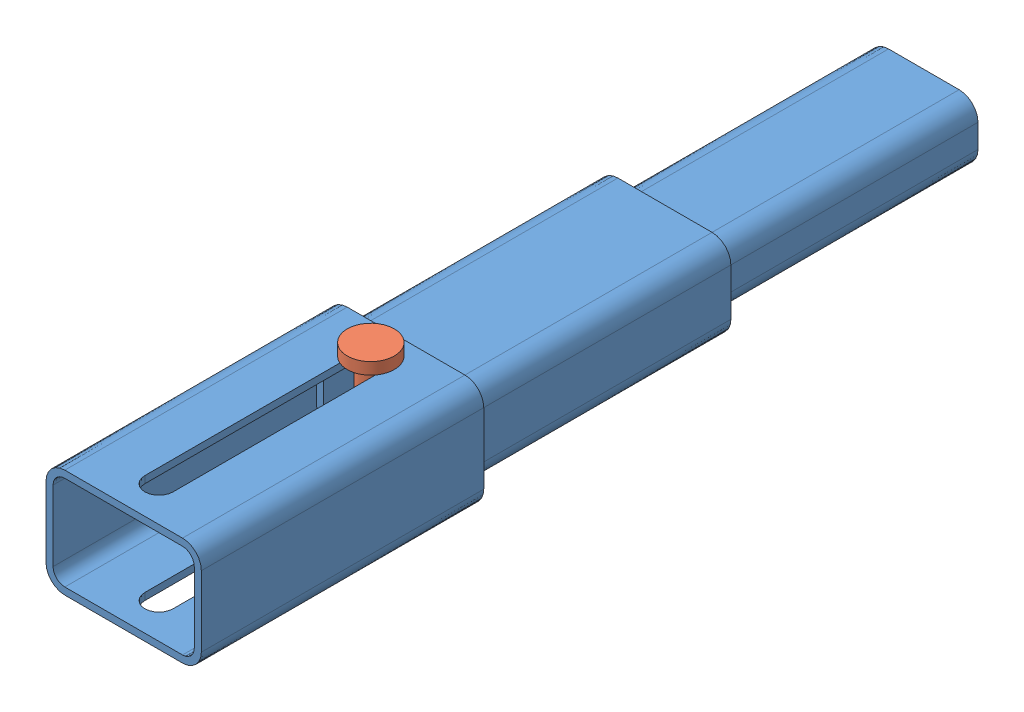
SolidWorks assembly advanced and mechanical mates, configuration Default. Lengths in mm.
Overall size (66 60 340).
4 component instances, 2 part files, 9 mates.
Components (placement in the parent):
- Advanced mates-1: Advanced mates [Large] at (58.4003 66.2101 82.4925) size (66 46 120)
- pin-1: pin [Default] at (58.4003 41.2101 37.4925) x (0.932523 0 -0.361112) z (0.361112 0 0.932523) size (20 60 20)
- Advanced mates-3: Advanced mates [Medium] at (58.4003 66.2101 -27.5075) size (56 36 120)
- Advanced mates-4: Advanced mates [Small] at (58.4003 66.2101 -137.5075) size (46 26 120)
Mates (geometry in assembly coordinates):
- Width1: width aligned: plane of Advanced mates-1 through (83.4003 46.2101 142.4925) normal (0 1 0); plane of Advanced mates-1 through (83.4003 86.2101 142.4925) normal (0 -1 0); plane of Advanced mates-3 through (78.4003 84.2101 32.4925) normal (0 1 0); plane of Advanced mates-3 through (78.4003 48.2101 32.4925) normal (0 -1 0)
- Width2: width anti-aligned: plane of Advanced mates-1 through (28.4003 51.2101 142.4925) normal (1 0 0); plane of Advanced mates-1 through (88.4003 51.2101 142.4925) normal (-1 0 0); plane of Advanced mates-3 through (30.4003 56.2101 32.4925) normal (-1 0 0); plane of Advanced mates-3 through (86.4003 56.2101 32.4925) normal (1 0 0)
- Width3: width anti-aligned: plane of Advanced mates-3 through (78.4003 81.2101 32.4925) normal (0 -1 0); plane of Advanced mates-3 through (78.4003 51.2101 32.4925) normal (0 1 0); plane of Advanced mates-4 through (73.4003 79.2101 -77.5075) normal (0 1 0); plane of Advanced mates-4 through (73.4003 53.2101 -77.5075) normal (0 -1 0)
- Width4: width anti-aligned: plane of Advanced mates-3 through (33.4003 56.2101 32.4925) normal (1 0 0); plane of Advanced mates-3 through (83.4003 56.2101 32.4925) normal (-1 0 0); plane of Advanced mates-4 through (78.4003 61.2101 -77.5075) normal (-1 0 0); plane of Advanced mates-4 through (38.4003 61.2101 -77.5075) normal (1 0 0)
- Coincident2: coincident aligned: plane of Advanced mates-1 through (33.4003 51.2101 142.4925) normal (0 0 1); plane of Advanced mates-3 through (38.4003 56.2101 142.4925) normal (0 0 1)
- Linear/Linear Coupler1: linear coupler = 1 : 2 mm: plane of Advanced mates-3 through (38.4003 56.2101 -87.5075) normal (0 0 -1); plane of Advanced mates-4 through (43.4003 61.2101 -197.5075) normal (0 0 -1)
- Slot1: slot anti-aligned: cylinder of pin-1 through (58.4003 91.2101 37.4925) axis (0 -1 0) radius 5; cylinder of Advanced mates-1 through (58.4003 43.2101 127.4925) axis (0 1 0) radius 6; cylinder of Advanced mates-1 through (58.4003 43.2101 37.4925) axis (0 1 0) radius 6
- Width5: width anti-aligned: plane of Advanced mates-1 through (83.4003 43.2101 142.4925) normal (0 -1 0); plane of Advanced mates-1 through (83.4003 89.2101 142.4925) normal (0 1 0); plane of pin-1 through (58.4003 41.2101 37.4925) normal (0 1 0); plane of pin-1 through (58.4003 91.2101 37.4925) normal (0 -1 0)
- Tangent1: tangent anti-aligned: cylinder of pin-1 through (58.4003 91.2101 37.4925) axis (0 -1 0) radius 5; plane of Advanced mates-3 through (38.4003 56.2101 32.4925) normal (0 0 1)
